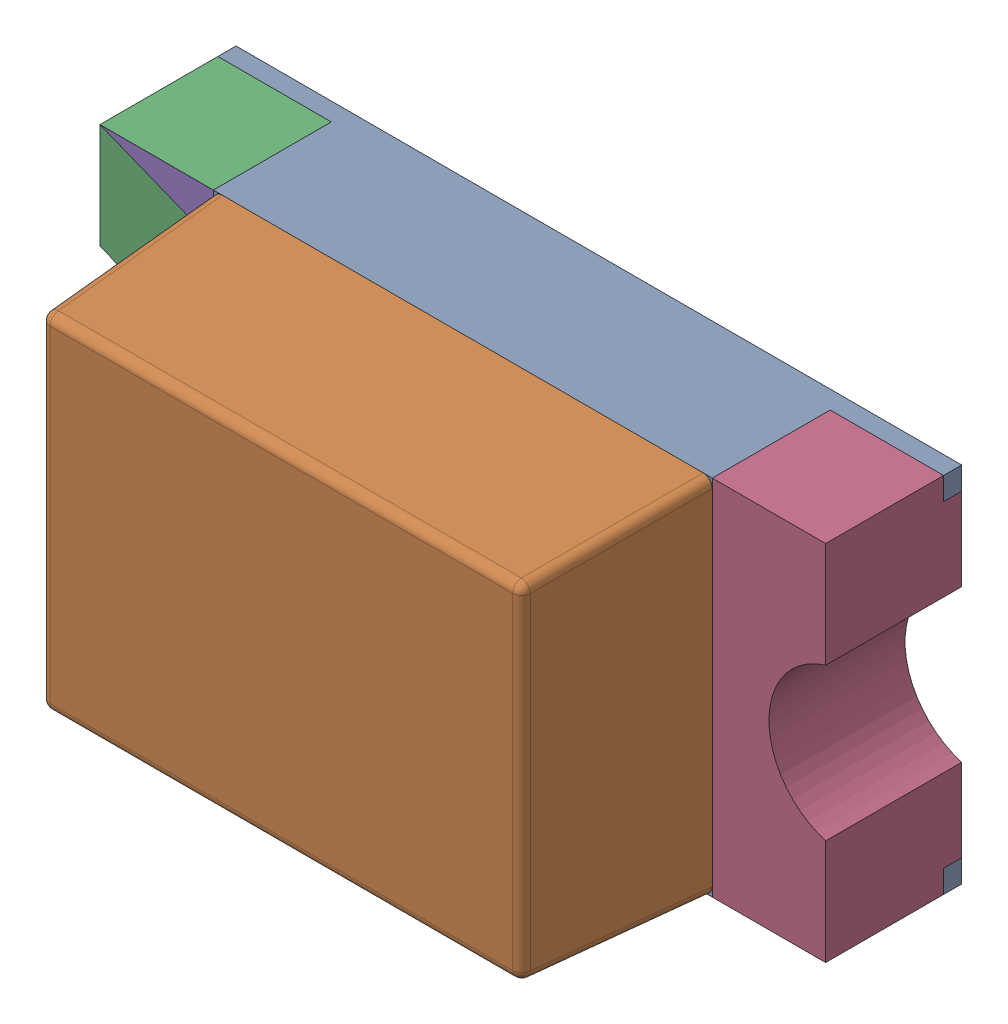
SolidWorks assembly WL-SMCW_0603_LED, configuration Default. Lengths in mm.
Overall size (1.6 0.8 0.7).
5 component instances, 4 part files, 0 mates.
Components (placement in the parent):
- housing-1: housing [Default] at origin size (1.6 0.8 0.3)
- cover-1: cover [Default] at (0 0 0.3) size (1.1 0.8 0.4)
- base-1: base [Default] at (-0.675 0 0) size (0.45 0.8 0.3)
- base-2: base [Default] at (0.675 0 0) x (-1 0 0) z (0 0 1) size (0.45 0.8 0.3)
- Polarity_Mark-1: Polarity_Mark [Default] at (-0.675 0.35 0.3) size (0.25 0.1 0)
